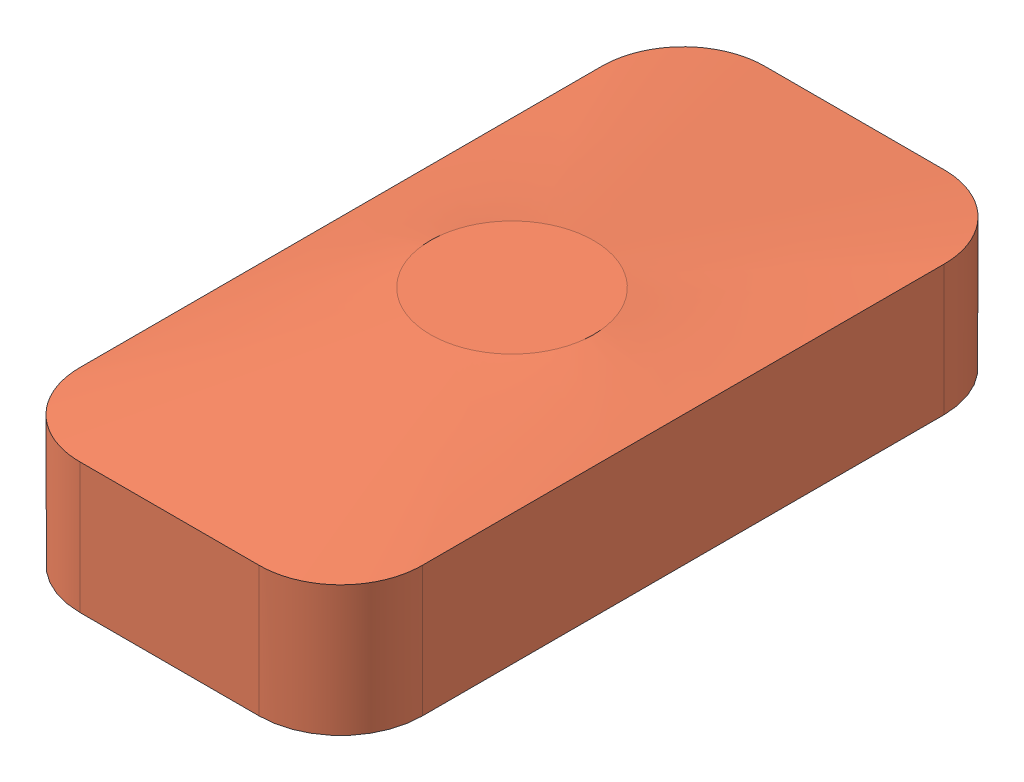
SolidWorks assembly Blue, configuration Default. Lengths in mm.
Overall size (21 9.51 42).
2 component instances, 2 part files, 3 mates.
Components (placement in the parent):
- blue lower-1: blue lower [Default] at origin size (17.4 6.5 38.4)
- blue upper-1: blue upper [Default] at (1.8 0 -1.8) x (0 0 1) z (-1 0 0) size (42 9.51 21)
Mates (geometry in assembly coordinates):
- Width1: width aligned: plane of blue upper-1 through (-17.7 6.5 3.2) normal (1 0 0); plane of blue lower-1 through (0.3 6.5 35.2) normal (-1 0 0); plane of blue upper-1 through (0 6.5 0) normal (1 0 0); plane of blue lower-1 through (-17.4 6.5 0) normal (-1 0 0)
- Width2: width aligned: plane of blue upper-1 through (-14.2 6.5 38.7) normal (0 0 -1); plane of blue lower-1 through (-3.2 6.5 -0.3) normal (0 0 1); plane of blue upper-1 through (0 6.5 0) normal (0 0 -1); plane of blue lower-1 through (0 6.5 38.4) normal (0 0 1)
- Coincident1: coincident aligned: plane of blue lower-1 through (0 0 0) normal (0 -1 0); plane of blue upper-1 through (1.8 0 -1.8) normal (0 -1 0)
